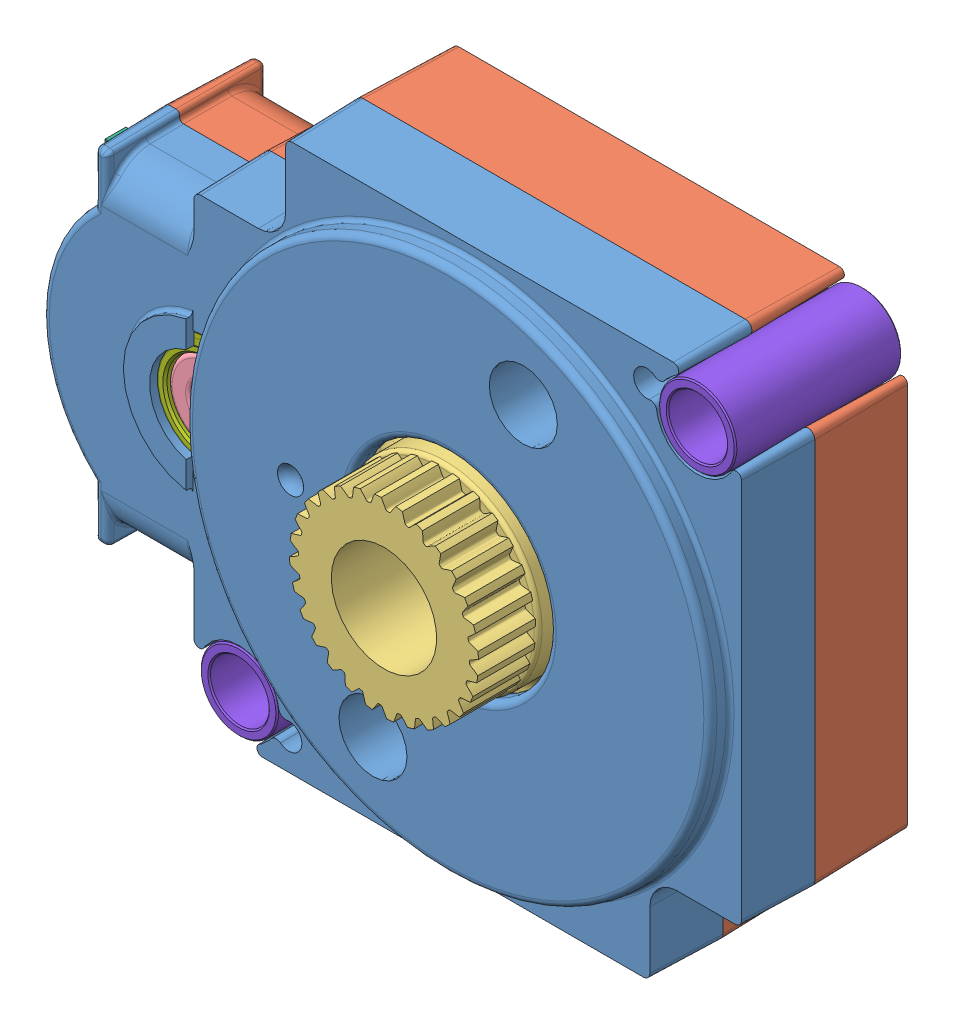
SolidWorks assembly VP Integrate Encoder 217-5046, configuration Default. Lengths in mm.
Overall size (56.84 43.13 21.2).
11 component instances, 10 part files, 0 mates.
Components (placement in the parent):
- 217-4783-001 Rev3-1: 217-4783-001 Rev3 [Default] at (0 0 2.75) size (53.55 42 11.11)
- 217-4783-002 Rev7_Sealed Config-1: 217-4783-002 Rev7_Sealed Config [Default] at (0 0 -7.2) x (0 1 0) z (0 0 1) size (42 51.56 9.32)
- 217-4783-005 Rev7_40t_spur_REF_14deg-1: 217-4783-005 Rev7_40t_spur_REF_14deg [Default] at (0 0 5.95) x (0.660339 0.750968 0) z (0 0 1) size (21.1 21.1 17.1)
- 217-4783-004 Rev2_40t_spur_REF_14deg-1: 217-4783-004 Rev2_40t_spur_REF_14deg [Default] at (-20.05 0 5.2) x (-0.718289 0.695745 0) z (0 0 1) size (21.07 21.07 4.88)
- 217-4783-008 Rev2-1: 217-4783-008 Rev2 [Default] at (-20.05 0 2.2) x (0.307149 -0.951661 0) z (0.951661 0.307149 0) size (5 4 5)
- PCBA Rev3-1: PCBA Rev3 [Default] at (-20.05 0 -2.1252) x (0 1 0) z (-1 0 0) size (15.93 8.7 23.21)
- 217-2788-001 Rev3_57155K375-1: 217-2788-001 Rev3_57155K375 [Default] at (-20.05 0 3.8125) x (-0.99574 0.092202 0) z (0 0 1) size (9.53 9.53 3.17)
- 217-4783-006 Rev3-1: 217-4783-006 Rev3 [Default] at (17.5 17.5 -0.85) x (-0.867641 0.497191 0) z (0 0 1) size (5.9 5.9 12.7)
- 217-4783-006 Rev3-2: 217-4783-006 Rev3 [Default] at (-17.5 -17.5 -0.85) x (0.825154 -0.564908 0) z (0 0 1) size (5.9 5.9 12.7)
- 217-4783-007 Rev1-1: 217-4783-007 Rev1 [Default] at (-16.45 0 -5.2) x (0 1 0) z (0 0 1) size (6 10.71 3.56)
- 217-4783-003 Rev4-1: 217-4783-003 Rev4 [Default] at (-20.05 0 -1.02) x (0 1 0) z (0 0 1) size (23.4 21.71 4.19)
